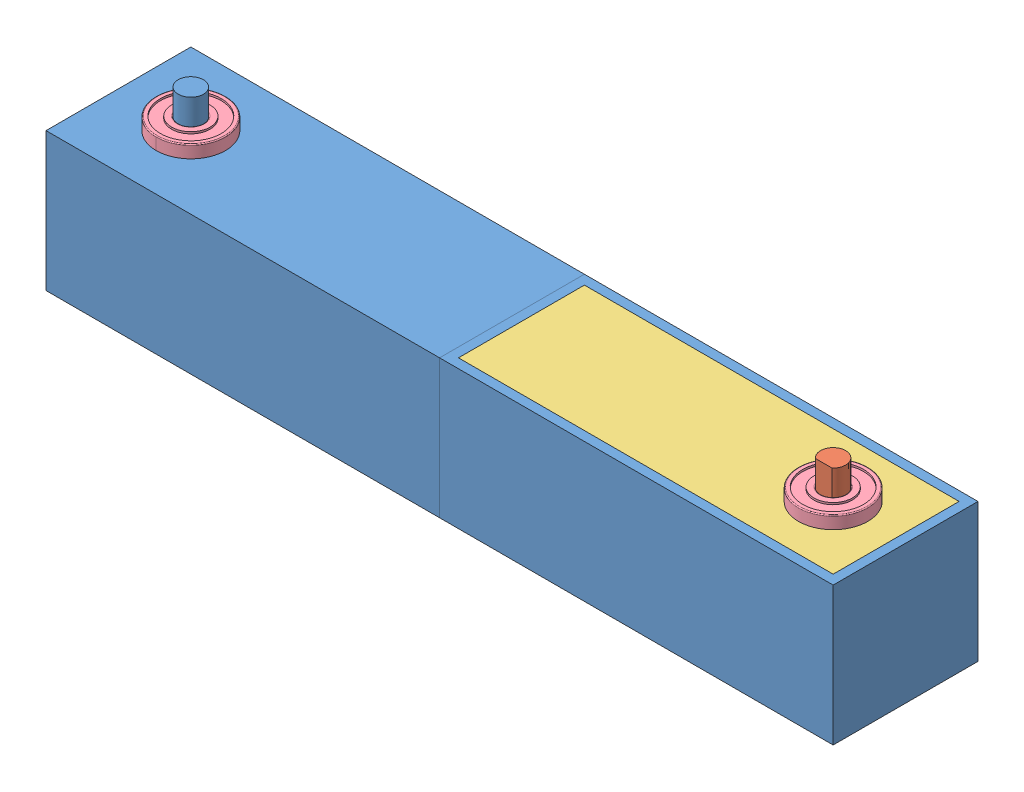
SolidWorks assembly Link3, configuration Default. Lengths in mm.
Overall size (250 68 46).
14 component instances, 4 part files, 5 mates.
Components (placement in the parent):
- Case2WithBearings-2: Case2WithBearings [Default] at origin size (125 68 46)
  - Motor2WithCase-1: Motor2WithCase [Default] at origin size (125 68 46) (flexible)
    - ArmBase2-1: ArmBase2 [Default] at origin size (125 56 46)
    - WormGearMotor-3: WormGearMotor [Default] at (-57.7 19.5 0) x (0 0 -1) z (0 -1 0) size (40 117.2 52)
    - ArmBaseCover-3: ArmBaseCover [Default] at (0 44 0) x (-1 0 0) z (0 0 1) size (119 4.5 40)
  - SB608ZZ-1: SB608ZZ [Default] at (39.5 48 0) x (0 -1 0) z (0.818908 0 -0.573924) size (7 22 22)
  - SB608ZZ-2: SB608ZZ [Default] at (39.5 3 0) x (0 -1 0) z (0 0 1) size (7 22 22)
- Case2WithBearings-3: Case2WithBearings [Default] at (-125 44 0) x (-1 0 0) z (0 0 1) size (125 68 46)
  - Motor2WithCase-1: Motor2WithCase [Default] at origin size (125 68 46) (flexible)
    - ArmBase2-1: ArmBase2 [Default] at origin size (125 56 46)
    - WormGearMotor-3: WormGearMotor [Default] at (-57.7 19.5 0) x (0 0 -1) z (0 -1 0) size (40 117.2 52)
    - ArmBaseCover-3: ArmBaseCover [Default] at (0 44 0) x (-1 0 0) z (0 0 1) size (119 4.5 40)
  - SB608ZZ-1: SB608ZZ [Default] at (39.5 48 0) x (0 -1 0) z (0.818908 0 -0.573924) size (7 22 22)
  - SB608ZZ-2: SB608ZZ [Default] at (39.5 3 0) x (0 -1 0) z (0 0 1) size (7 22 22)
Mates (geometry in assembly coordinates):
- Coincident4: coincident aligned: plane of Case2WithBearings-2/Motor2WithCase-1/ArmBase2-1 through (-62.5 44 -23) normal (0 0 -1); plane of Case2WithBearings-3/Motor2WithCase-1/ArmBase2-1 through (-62.5 0 -23) normal (0 0 -1)
- Coincident5: coincident anti-aligned: plane of Case2WithBearings-2/Motor2WithCase-1/ArmBase2-1 through (-62.5 44 23) normal (-1 0 0); plane of Case2WithBearings-3/Motor2WithCase-1/ArmBase2-1 through (-62.5 0 23) normal (1 0 0)
- Coincident6: coincident aligned: plane of Case2WithBearings-2/Motor2WithCase-1/ArmBaseCover-2 through (29.359 6.4726 -157.5219) normal (0.089391 0.987096 -0.132857); plane of Case2WithBearings-3/Motor2WithCase-1/ArmBase2-1 through (-125 44 0) normal (0 1 0)
- Coincident7: coordinate: point of Case2WithBearings-2
- Coincident8: coincident aligned: plane of Case2WithBearings-2/Motor2WithCase-1/ArmBaseCover-3 through (0 44 0) normal (0 1 0); plane of Case2WithBearings-3/Motor2WithCase-1/ArmBase2-1 through (-125 44 0) normal (0 1 0)
